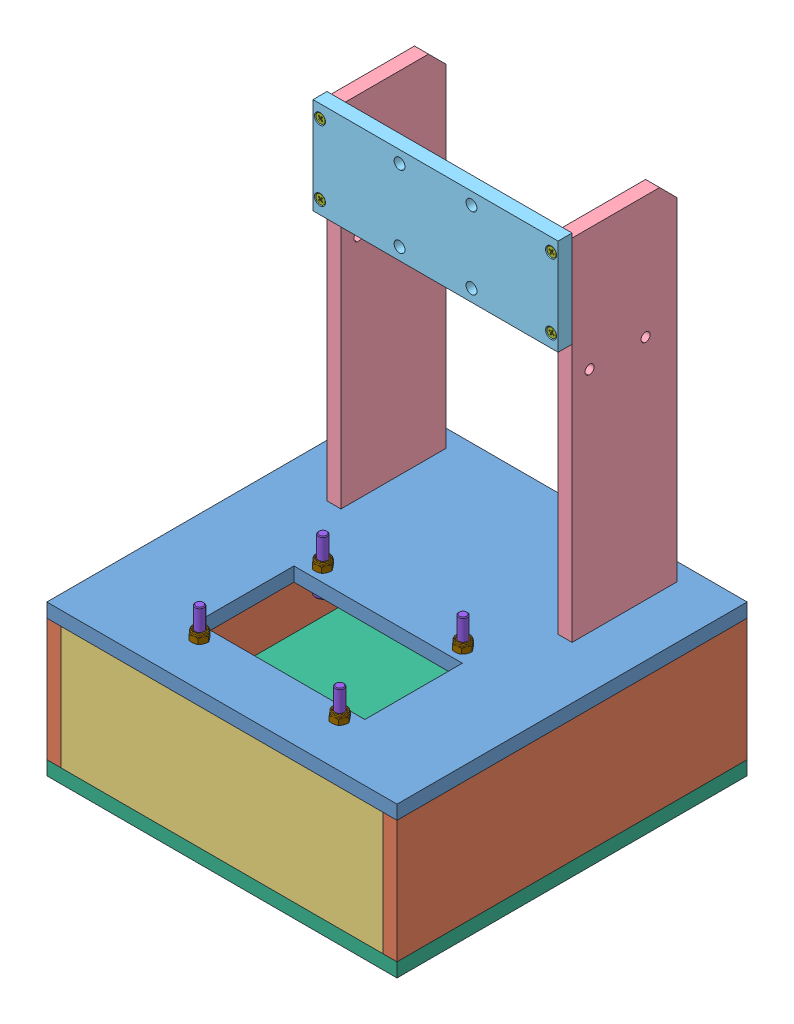
SolidWorks assembly PressMachine, configuration Default. Lengths in mm.
Overall size (200 288.5 200).
21 component instances, 9 part files, 49 mates.
Components (placement in the parent):
- table^PressMachine-1: table^PressMachine [Default] at (9.2688 70 -44.9923) size (200 8 200) (virtual)
- SideWall^PressMachine-1: SideWall^PressMachine [ConnectorsSide] at (-86.7312 0 55.0077) size (8 70 200) (virtual)
- SideWall^PressMachine-2: SideWall^PressMachine [ClearSide] at (105.2688 0 55.0077) size (8 70 200) (virtual)
- Front^PressMachine-1: Front^PressMachine [Default] at (9.2688 35 51.0077) size (184 70 8) (virtual)
- VerticalWall^PressMachine-1: VerticalWall^PressMachine [Default] at (-56.7312 78 -74.9923) size (8 200 60) (virtual)
- VerticalWall^PressMachine-2: VerticalWall^PressMachine [Default] at (75.2688 78 -74.9923) size (8 200 60) (virtual)
- ClampBase^PressMachine-1: ClampBase^PressMachine [Default] at (9.2688 253 -74.9923) size (140 55 8) (virtual)
- BottomSideOfEquipment^PressMachine-1: BottomSideOfEquipment^PressMachine [Default] at (9.2688 -8 -44.9923) size (200 8 200) (virtual)
- Self Tapping Cross recessed Screw4Plastic DIN7982 M3^PressMachine-1: Self Tapping Cross recessed Screw4Plastic DIN7982 M3^PressMachine [20mm] at (-56.7312 273 -67.2923) x (0 0 -1) z (0.741038 -0.671463 0) size (20 5.3 5.3) (virtual)
- Self Tapping Cross recessed Screw4Plastic DIN7982 M3^PressMachine-2: Self Tapping Cross recessed Screw4Plastic DIN7982 M3^PressMachine [20mm] at (-56.7312 233 -67.2923) x (0 0 -1) z (0.741038 -0.671463 0) size (20 5.3 5.3) (virtual)
- Self Tapping Cross recessed Screw4Plastic DIN7982 M3^PressMachine-3: Self Tapping Cross recessed Screw4Plastic DIN7982 M3^PressMachine [20mm] at (75.2688 273 -67.2923) x (0 0 -1) z (0.914131 -0.405419 0) size (20 5.3 5.3) (virtual)
- Self Tapping Cross recessed Screw4Plastic DIN7982 M3^PressMachine-4: Self Tapping Cross recessed Screw4Plastic DIN7982 M3^PressMachine [20mm] at (75.2688 233 -67.2923) x (0 0 -1) z (0.914131 -0.405419 0) size (20 5.3 5.3) (virtual)
- Front^PressMachine-2: Front^PressMachine [Default] at (9.2688 35 -140.9923) size (184 70 8) (virtual)
- socket head cap screw_din-1: socket head cap screw_din [DIN 912 M5 x 25 --- 25N] at (-28.937 65 29.547) x (0 1 0) z (-0.513704 0 0.857968) size (30 8.5 8.5)
- socket head cap screw_din-2: socket head cap screw_din [DIN 912 M5 x 25 --- 25N] at (-28.937 65 -40.8751) x (0 1 0) z (-0.513704 0 0.857968) size (30 8.5 8.5)
- socket head cap screw_din-3: socket head cap screw_din [DIN 912 M5 x 25 --- 25N] at (51.1079 65 29.547) x (0 1 0) z (-0.513704 0 0.857968) size (30 8.5 8.5)
- socket head cap screw_din-4: socket head cap screw_din [DIN 912 M5 x 25 --- 25N] at (51.1079 65 -40.8751) x (0 1 0) z (-0.513704 0 0.857968) size (30 8.5 8.5)
- Nyloc nut St_Steel A2 ISO M2_5-M36-1: Nyloc nut St_Steel A2 ISO M2_5-M36 [M5 NYLOC] at (-28.937 78 -40.8751) x (0.991041 0 -0.133555) z (0.133555 0 0.991041) size (9.24 5 8)
- Nyloc nut St_Steel A2 ISO M2_5-M36-2: Nyloc nut St_Steel A2 ISO M2_5-M36 [M5 NYLOC] at (-28.937 78 29.547) x (0.991041 0 -0.133555) z (0.133555 0 0.991041) size (9.24 5 8)
- Nyloc nut St_Steel A2 ISO M2_5-M36-3: Nyloc nut St_Steel A2 ISO M2_5-M36 [M5 NYLOC] at (51.1079 78 -40.8751) x (0.991041 0 -0.133555) z (0.133555 0 0.991041) size (9.24 5 8)
- Nyloc nut St_Steel A2 ISO M2_5-M36-4: Nyloc nut St_Steel A2 ISO M2_5-M36 [M5 NYLOC] at (51.1079 78 29.547) x (0.991041 0 -0.133555) z (0.133555 0 0.991041) size (9.24 5 8)
Mates (geometry in assembly coordinates):
- Coincident1: coincident aligned: plane of table^pressMachine_ManualPCBsTestingEquipment-1 through (-90.7312 78 55.0077) normal (-1 0 0); plane of SideWall^pressMachine_ManualPCBsTestingEquipment-1 through (-90.7312 0 55.0077) normal (-1 0 0)
- Coincident2: coincident anti-aligned: plane of table^pressMachine_ManualPCBsTestingEquipment-1 through (9.2688 70 -44.9923) normal (0 -1 0); plane of SideWall^pressMachine_ManualPCBsTestingEquipment-2 through (109.2688 70 55.0077) normal (0 1 0)
- Coincident3: coincident aligned: plane of table^pressMachine_ManualPCBsTestingEquipment-1 through (109.2688 78 55.0077) normal (1 0 0); plane of SideWall^pressMachine_ManualPCBsTestingEquipment-2 through (109.2688 0 55.0077) normal (1 0 0)
- Coincident4: coincident aligned: plane of table^pressMachine_ManualPCBsTestingEquipment-1 through (-90.7312 78 55.0077) normal (-1 0 0); plane of SideWall^pressMachine_ManualPCBsTestingEquipment-1 through (-90.7312 0 55.0077) normal (-1 0 0)
- Coincident5: coincident aligned: plane of table^pressMachine_ManualPCBsTestingEquipment-1 through (109.2688 78 55.0077) normal (0 0 1); plane of SideWall^pressMachine_ManualPCBsTestingEquipment-2 through (109.2688 0 55.0077) normal (0 0 1)
- Coincident6: coincident aligned: plane of table^pressMachine_ManualPCBsTestingEquipment-1 through (109.2688 78 55.0077) normal (0 0 1); plane of SideWall^pressMachine_ManualPCBsTestingEquipment-1 through (-82.7312 0 55.0077) normal (0 0 1)
- Coincident7: coincident anti-aligned: plane of table^pressMachine_ManualPCBsTestingEquipment-1 through (9.2688 70 -44.9923) normal (0 -1 0); plane of SideWall^pressMachine_ManualPCBsTestingEquipment-1 through (-82.7312 70 55.0077) normal (0 1 0)
- Coincident8: coincident anti-aligned: plane of table^pressMachine_ManualPCBsTestingEquipment-1 through (9.2688 70 -44.9923) normal (0 -1 0); plane of Front^pressMachine_ManualPCBsTestingEquipment-1 through (101.2688 70 55.0077) normal (0 1 0)
- Coincident9: coincident aligned: plane of table^pressMachine_ManualPCBsTestingEquipment-1 through (109.2688 78 55.0077) normal (0 0 1); plane of Front^pressMachine_ManualPCBsTestingEquipment-1 through (9.2688 35 55.0077) normal (0 0 1)
- Coincident10: coincident anti-aligned: plane of SideWall^pressMachine_ManualPCBsTestingEquipment-2 through (101.2688 0 55.0077) normal (-1 0 0); plane of Front^pressMachine_ManualPCBsTestingEquipment-1 through (101.2688 0 55.0077) normal (1 0 0)
- Coincident11: coincident anti-aligned: plane of table^pressMachine_ManualPCBsTestingEquipment-1 through (9.2688 78 -44.9923) normal (0 1 0); plane of VerticalWall^pressMachine_ManualPCBsTestingEquipment-1 through (-52.7312 78 -134.9923) normal (0 -1 0)
- Coincident12: coincident anti-aligned: plane of SideWall^pressMachine_ManualPCBsTestingEquipment-1 through (-82.7312 0 -144.9923) normal (0 -1 0)
- Coincident13: coincident anti-aligned: plane of table^pressMachine_ManualPCBsTestingEquipment-1 through (9.2688 78 -44.9923) normal (0 1 0); plane of VerticalWall^pressMachine_ManualPCBsTestingEquipment-2 through (79.2688 78 -134.9923) normal (0 -1 0)
- Coincident15: coincident anti-aligned: plane of VerticalWall^pressMachine_ManualPCBsTestingEquipment-2 through (79.2688 78 -74.9923) normal (0 0 1); plane of ClampBase^pressMachine_ManualPCBsTestingEquipment-1 through (9.2688 253 -74.9923) normal (0 0 -1)
- Coincident16: coincident anti-aligned: plane of VerticalWall^pressMachine_ManualPCBsTestingEquipment-1 through (-52.7312 78 -74.9923) normal (0 0 1); plane of ClampBase^pressMachine_ManualPCBsTestingEquipment-1 through (9.2688 253 -74.9923) normal (0 0 -1)
- Coincident19: coincident aligned: plane of SideWall^pressMachine_ManualPCBsTestingEquipment-1 through (-90.7312 0 55.0077) normal (-1 0 0); plane of BottomSideOfEquipment^pressMachine_ManualPCBsTestingEquipment-1 through (-90.7312 0 55.0077) normal (-1 0 0)
- Coincident20: coincident anti-aligned: plane of SideWall^pressMachine_ManualPCBsTestingEquipment-1 through (-82.7312 0 -144.9923) normal (0 -1 0); plane of BottomSideOfEquipment^pressMachine_ManualPCBsTestingEquipment-1 through (9.2688 0 -44.9923) normal (0 1 0)
- Coincident21: coincident aligned: plane of SideWall^pressMachine_ManualPCBsTestingEquipment-1 through (-82.7312 0 55.0077) normal (0 0 1); plane of Copy of BottomSideOfEquipment^pressMachine_ManualPCBsTestingEquipment-1 through (109.2688 0 55.0077) normal (0 0 1)
- Concentric1: concentric anti-aligned: cylinder of ClampBase^pressMachine_ManualPCBsTestingEquipment-1 through (-56.7312 273 -66.9923) axis (0 0 1) radius 1.6; cylinder of Self Tapping Cross recessed Screw4Plastic DIN7982 M3^pressMachine_ManualPCBsTestingEquipment-1 through (-56.7312 273 -87.2923) axis (0 0 -1) radius 1
- Coincident22: coincident aligned: cone of ClampBase^pressMachine_ManualPCBsTestingEquipment-1 through (-56.7312 273 -66.9923) axis (0 0 -1); cone of Self Tapping Cross recessed Screw4Plastic DIN7982 M3^pressMachine_ManualPCBsTestingEquipment-1 through (-56.7312 273 -69.1423) axis (0 0 -1)
- Concentric2: concentric anti-aligned: cylinder of VerticalWall^pressMachine_ManualPCBsTestingEquipment-1 through (-56.7312 273 -74.9923) axis (0 0 1) radius 1; cylinder of Self Tapping Cross recessed Screw4Plastic DIN7982 M3^pressMachine_ManualPCBsTestingEquipment-1 through (-56.7312 273 -87.2923) axis (0 0 -1) radius 1
- Concentric3: concentric anti-aligned: cylinder of ClampBase^pressMachine_ManualPCBsTestingEquipment-1 through (-56.7312 233 -66.9923) axis (0 0 1) radius 1.6; cylinder of Self Tapping Cross recessed Screw4Plastic DIN7982 M3^pressMachine_ManualPCBsTestingEquipment-2 through (-56.7312 233 -87.2923) axis (0 0 -1) radius 1
- Coincident23: coincident aligned: cone of ClampBase^pressMachine_ManualPCBsTestingEquipment-1 through (-56.7312 233 -66.9923) axis (0 0 -1); cone of Self Tapping Cross recessed Screw4Plastic DIN7982 M3^pressMachine_ManualPCBsTestingEquipment-2 through (-56.7312 233 -69.1423) axis (0 0 -1)
- Concentric4: concentric anti-aligned: cylinder of VerticalWall^pressMachine_ManualPCBsTestingEquipment-1 through (-56.7312 233 -74.9923) axis (0 0 1) radius 1; cylinder of Self Tapping Cross recessed Screw4Plastic DIN7982 M3^pressMachine_ManualPCBsTestingEquipment-2 through (-56.7312 233 -87.2923) axis (0 0 -1) radius 1
- Concentric5: concentric anti-aligned: cylinder of ClampBase^pressMachine_ManualPCBsTestingEquipment-1 through (75.2688 273 -66.9923) axis (0 0 1) radius 1.6; cylinder of Self Tapping Cross recessed Screw4Plastic DIN7982 M3^pressMachine_ManualPCBsTestingEquipment-3 through (75.2688 273 -87.2923) axis (0 0 -1) radius 1
- Concentric6: concentric anti-aligned: cylinder of ClampBase^pressMachine_ManualPCBsTestingEquipment-1 through (75.2688 233 -66.9923) axis (0 0 1) radius 1.6; cylinder of Self Tapping Cross recessed Screw4Plastic DIN7982 M3^pressMachine_ManualPCBsTestingEquipment-4 through (75.2688 233 -87.2923) axis (0 0 -1) radius 1
- Coincident24: coincident aligned: cone of ClampBase^pressMachine_ManualPCBsTestingEquipment-1 through (75.2688 273 -66.9923) axis (0 0 -1); cone of Self Tapping Cross recessed Screw4Plastic DIN7982 M3^pressMachine_ManualPCBsTestingEquipment-3 through (75.2688 273 -69.1423) axis (0 0 -1)
- Coincident25: coincident aligned: cone of ClampBase^pressMachine_ManualPCBsTestingEquipment-1 through (75.2688 233 -66.9923) axis (0 0 -1); cone of Self Tapping Cross recessed Screw4Plastic DIN7982 M3^pressMachine_ManualPCBsTestingEquipment-4 through (75.2688 233 -69.1423) axis (0 0 -1)
- Concentric7: concentric anti-aligned: cylinder of VerticalWall^pressMachine_ManualPCBsTestingEquipment-2 through (75.2688 273 -74.9923) axis (0 0 1) radius 1; cylinder of Self Tapping Cross recessed Screw4Plastic DIN7982 M3^pressMachine_ManualPCBsTestingEquipment-3 through (75.2688 273 -87.2923) axis (0 0 -1) radius 1
- Concentric8: concentric anti-aligned: cylinder of table^pressMachine_ManualPCBsTestingEquipment-1 through (-56.7312 70 -129.9923) axis (0 1 0) radius 2; cylinder of VerticalWall^pressMachine_ManualPCBsTestingEquipment-1 through (-56.7312 78 -129.9923) axis (0 -1 0) radius 1
- Coincident26: coincident anti-aligned: plane of BottomSideOfEquipment^pressMachine_ManualPCBsTestingEquipment-1 through (9.2688 0 -44.9923) normal (0 1 0); plane of Front^pressMachine_ManualPCBsTestingEquipment-2 through (101.2688 0 -136.9923) normal (0 -1 0)
- Coincident27: coincident aligned: plane of BottomSideOfEquipment^pressMachine_ManualPCBsTestingEquipment-1 through (109.2688 0 -144.9923) normal (0 0 -1); plane of Front^pressMachine_ManualPCBsTestingEquipment-2 through (9.2688 35 -144.9923) normal (0 0 -1)
- Coincident28: coincident anti-aligned: plane of SideWall^pressMachine_ManualPCBsTestingEquipment-2 through (101.2688 0 55.0077) normal (-1 0 0); plane of Front^pressMachine_ManualPCBsTestingEquipment-2 through (101.2688 0 -136.9923) normal (1 0 0)
- Concentric9: concentric anti-aligned: cylinder of table^pressMachine_ManualPCBsTestingEquipment-1 through (-28.937 78 29.547) axis (0 1 0) radius 2.6; cylinder of socket head cap screw_din-1 through (-28.937 33.25 29.547) axis (0 -1 0) radius 2.5
- Coincident29: coincident anti-aligned: plane of table^pressMachine_ManualPCBsTestingEquipment-1 through (9.2688 70 -44.9923) normal (0 -1 0); plane of socket head cap screw_din-1 through (-32.5834 70 27.3637) normal (0 1 0)
- Concentric101: concentric anti-aligned: cylinder of table^pressMachine_ManualPCBsTestingEquipment-1 through (-28.937 78 -40.8751) axis (0 1 0) radius 2.6; cylinder of socket head cap screw_din-2 through (-28.937 33.25 -40.8751) axis (0 -1 0) radius 4.25
- Coincident301: coincident anti-aligned: plane of table^pressMachine_ManualPCBsTestingEquipment-1 through (9.2688 70 -44.9923) normal (0 -1 0); plane of socket head cap screw_din-2 through (-32.5834 70 -43.0583) normal (0 1 0)
- Concentric111: concentric anti-aligned: cylinder of table^pressMachine_ManualPCBsTestingEquipment-1 through (51.1079 78 29.547) axis (0 1 0) radius 2.6; cylinder of socket head cap screw_din-3 through (51.1079 33.25 29.547) axis (0 -1 0) radius 4.25
- Coincident311: coincident anti-aligned: plane of table^pressMachine_ManualPCBsTestingEquipment-1 through (9.2688 70 -44.9923) normal (0 -1 0); plane of socket head cap screw_din-3 through (47.4616 70 27.3637) normal (0 1 0)
- Concentric121: concentric anti-aligned: cylinder of table^pressMachine_ManualPCBsTestingEquipment-1 through (51.1079 78 -40.8751) axis (0 1 0) radius 2.6; cylinder of socket head cap screw_din-4 through (51.1079 33.25 -40.8751) axis (0 -1 0) radius 4.25
- Coincident321: coincident anti-aligned: plane of table^pressMachine_ManualPCBsTestingEquipment-1 through (9.2688 70 -44.9923) normal (0 -1 0); plane of socket head cap screw_din-4 through (47.4616 70 -43.0583) normal (0 1 0)
- Coincident33: coincident anti-aligned: plane of table^pressMachine_ManualPCBsTestingEquipment-1 through (9.2688 78 -44.9923) normal (0 1 0); plane of Nyloc nut St_Steel A2 ISO M2_5-M36-1 through (-27.8686 78 -32.9467) normal (0 -1 0)
- Concentric13: concentric anti-aligned: cylinder of socket head cap screw_din-2 through (-28.937 33.25 -40.8751) axis (0 -1 0) radius 2.5; cylinder of Nyloc nut St_Steel A2 ISO M2_5-M36-1 through (-28.937 78 -40.8751) axis (0 1 0) radius 2.01
- Concentric141: concentric aligned: cylinder of socket head cap screw_din-1 through (-28.937 33.25 29.547) axis (0 -1 0) radius 2.5; cylinder of Nyloc nut St_Steel A2 ISO M2_5-M36-2 through (-28.937 83 29.547) axis (0 -1 0) radius 4
- Coincident34: coincident anti-aligned: plane of table^pressMachine_ManualPCBsTestingEquipment-1 through (9.2688 78 -44.9923) normal (0 1 0); plane of Nyloc nut St_Steel A2 ISO M2_5-M36-2 through (-27.8686 78 37.4753) normal (0 -1 0)
- Concentric151: concentric aligned: cylinder of socket head cap screw_din-4 through (51.1079 33.25 -40.8751) axis (0 -1 0) radius 2.5; cylinder of Nyloc nut St_Steel A2 ISO M2_5-M36-3 through (51.1079 83 -40.8751) axis (0 -1 0) radius 4
- Concentric161: concentric aligned: cylinder of socket head cap screw_din-3 through (51.1079 33.25 29.547) axis (0 -1 0) radius 2.5; cylinder of Nyloc nut St_Steel A2 ISO M2_5-M36-4 through (51.1079 83 29.547) axis (0 -1 0) radius 4
- Coincident35: coincident anti-aligned: plane of table^pressMachine_ManualPCBsTestingEquipment-1 through (9.2688 78 -44.9923) normal (0 1 0); plane of Nyloc nut St_Steel A2 ISO M2_5-M36-4 through (52.1764 78 37.4753) normal (0 -1 0)
- Coincident36: coincident anti-aligned: plane of table^pressMachine_ManualPCBsTestingEquipment-1 through (9.2688 78 -44.9923) normal (0 1 0); plane of Nyloc nut St_Steel A2 ISO M2_5-M36-3 through (52.1764 78 -32.9467) normal (0 -1 0)
